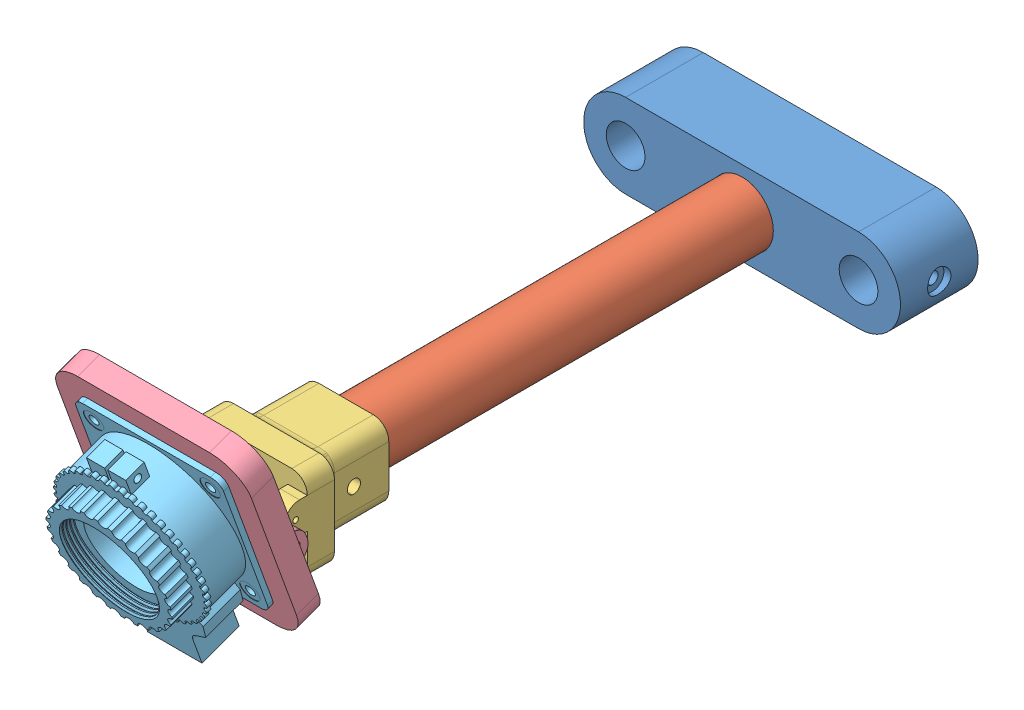
SolidWorks assembly camera subassembly, configuration Default. Lengths in mm.
Overall size (81.6 62.53 190.48).
6 component instances, 5 part files, 10 mates.
Components (placement in the parent):
- better camera base-2: better camera base [Default] at origin size (81.6 21.6 20)
- camera_tube-1: camera_tube [Default] x (0 1 0) z (1 0 0) size (16 140 16)
- CAMERA_ASSEMBLY-1: CAMERA_ASSEMBLY [Default] at (0 0 140) size (50 62.53 68.48)
  - New_CAM-Mount-1: New_CAM-Mount [Default] at origin size (30 24 31)
  - Camera_Plate-4: Camera_Plate [Default] at (0.05 10.7075 20.0015) x (0 -0.34202 0.939693) z (-1 0 0) size (12 50 50)
  - Raspberry Pi HQ Camera-1: Raspberry Pi HQ Camera [Default] at (-18.95 26.5095 32.138) x (1 0 0) z (0 -0.939693 -0.34202) size (38 20.12 51.85)
Mates (geometry in assembly coordinates):
- Coincident3: coordinate: point of better camera base-2
- Concentric3: concentric aligned: cylinder of better camera base-2 through (0 0 20) axis (0 0 -1) radius 8.05; cylinder of camera rod-2 through (0 0 143.4008) axis (0 0 -1) radius 5
- Concentric5: concentric anti-aligned: cylinder of camera rod-2 through (0 0 143.4008) axis (0 0 -1) radius 5; cylinder of camera cap-4 through (0 0 128) axis (0 0 1) radius 8
- Parallel4: parallel aligned: line of better camera base-2 through (-30 -10.8 20) axis (1 0 0); line of camera cap-4 through (-12 -12 153) axis (1 0 0)
- Distance4: distance = 133 mm aligned: plane of camera cap-4 through (0 0 153) normal (0 0 1); plane of better camera base-2 through (-30 0 20) normal (0 0 1)
- Concentric6: concentric aligned: cylinder of better camera base-2 through (0 0 20) axis (0 0 -1) radius 8.05; cylinder of camera_tube-1 through (0 0 140) axis (0 0 -1) radius 8
- Coincident4: coincident aligned: plane of better camera base-2 through (-30 0 0) normal (0 0 -1); plane of camera_tube-1 through (0 0 0) normal (0 0 -1)
- Concentric7: concentric anti-aligned: cylinder of camera_tube-1 through (0 0 140) axis (0 0 -1) radius 8; cylinder of CAMERA_ASSEMBLY-1/New_CAM-Mount-1 through (0 0 106) axis (0 0 1) radius 8
- Coincident5: coincident anti-aligned: plane of camera_tube-1 through (0 0 140) normal (0 0 1); plane of CAMERA_ASSEMBLY-1/New_CAM-Mount-1 through (0 0 140) normal (0 0 -1)
- Parallel5: parallel aligned: line of better camera base-2 through (30 10.8 20) axis (-1 0 0); line of CAMERA_ASSEMBLY-1/New_CAM-Mount-1 through (7 9.5 122) axis (-1 0 0)
